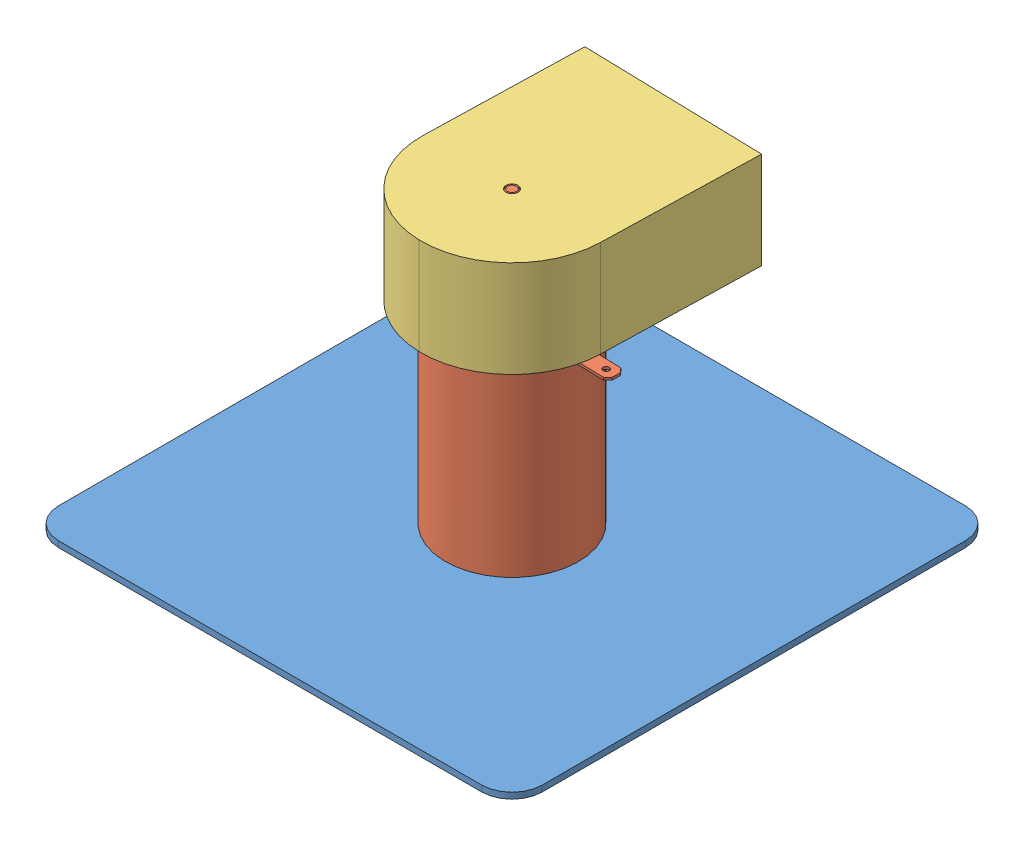
SolidWorks assembly test, configuration Défaut. Lengths in mm.
Overall size (80 54.4 80).
7 component instances, 4 part files, 4 mates.
Components (placement in the parent):
- PlaqueMoteur80_80-1: PlaqueMoteur80_80 [Défaut] at (-43.4652 29.4519 0) size (80 1 80)
- Codeur+Moteur-1: Codeur+Moteur [Défaut] at (9.181 51.4236 -39.6743) x (0.999669 0 0.025744) z (0.025744 0 -0.999669) size (35.4 54.4 41)
  - AMAX_22_CLL-1: AMAX_22_CLL [Default] at (-12.6505 -10.9283 0) size (35.4 54.4 22)
  - HEDS5540-1: HEDS5540 [Défaut] at (-27.6505 -26.9283 26) size (30 16 41)
- Slotted Countersunk Flat Head Screw_ISO-2: Slotted Countersunk Flat Head Screw_ISO [ISO 2009 - M2 x 5 --- 5C] at (-9.4652 36.0241 -40) x (0 1 0) z (-0.546944 0 0.837169) (suppressed, hidden)
- Slotted Countersunk Flat Head Screw_ISO-3: Slotted Countersunk Flat Head Screw_ISO [ISO 2009 - M2 x 5 --- 5C] at (-9.4652 29.2519 -40) x (0 1 0) z (0.546944 0 -0.837169)
- Slotted Countersunk Flat Head Screw_ISO-4: Slotted Countersunk Flat Head Screw_ISO [ISO 2009 - M2 x 5 --- 5C] at (2.5348 29.2519 -40) x (0 1 0) z (0.546944 0 -0.837169)
Mates (geometry in assembly coordinates):
- Coïncidente1: coincident aligned: circle of PlaqueMoteur80_80-1; circle of Codeur+Moteur-1/AMAX_22_CLL-1
- Coaxiale1: concentric anti-aligned: circle of PlaqueMoteur80_80-1; circle of Codeur+Moteur-1/AMAX_22_CLL-1
- Coïncidente21: coincident aligned: cone of PlaqueMoteur80_80-1
- Coïncidente31: coincident aligned: unknown of PlaqueMoteur80_80-1
